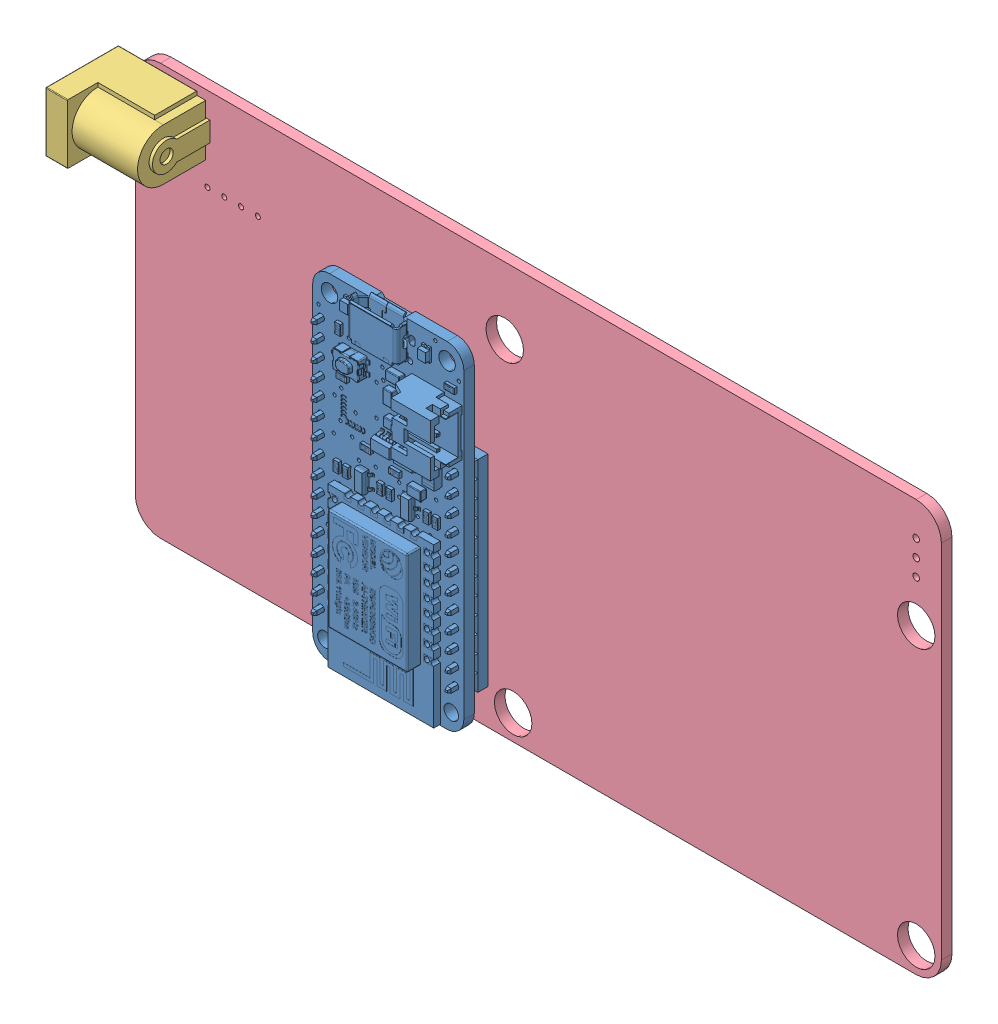
SolidWorks assembly me-freeledmodel, configuration Défaut. Lengths in mm.
Overall size (125.18 62.87 58.05).
9 component instances, 4 part files, 0 mates.
Components (placement in the parent):
- Adafruit_ESP8266_Feather_withPinheads-1: Adafruit_ESP8266_Feather_withPinheads [Défaut] at (77.45 -64.5 3.65) x (-1 0 0) z (0 1 0) size (22.89 14.76 51.51)
  - COMPOUND-1: COMPOUND [Défaut] at origin size (22.89 14.76 51.51)
- R_1206-1: R_1206 [Défaut] at (65.31 -92.71 1.65) size (3.2 1.6 0.55)
  - SOLID-1: SOLID [Défaut] at origin size (3.2 1.6 0.55)
- R_1206-2: R_1206 [Défaut] at (65.31 -85.09 1.65) size (3.2 1.6 0.55)
  - SOLID-1: SOLID [Défaut] at origin size (3.2 1.6 0.55)
- barrel-1: barrel [Défaut] at (34.925 -58.547 8.15) size (13.7 9.55 14.6)
  - COMPOUND_2-1: COMPOUND_2 [Défaut] at origin size (13.7 9.55 14.6)
- COMPOUND_3-1: COMPOUND_3 [Défaut] at origin size (122.77 62.87 1.6)
